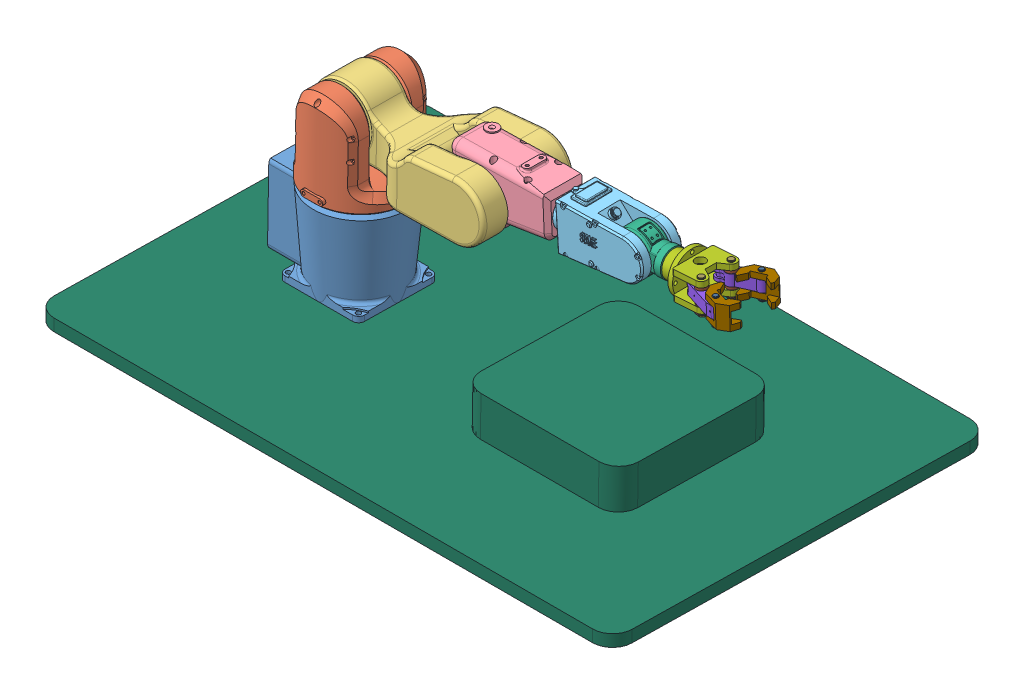
SolidWorks assembly ROBOT2, configuration 默认. Lengths in mm.
Overall size (1469.52 562.89 964.73).
25 component instances, 15 part files, 12 mates.
Components (placement in the parent):
- 0-1: 0 [默认] at (0 72.9247 -71.4969) x (1 0 0) z (0 0.017452 0.999848) size (299.76 239.19 271.11)
- 1_1-1: 1_1 [默认] at (0 293.8911 -75.3539) x (-0.009855 -0.017452 -0.999799) z (0.999951 -0.000172 -0.009854) size (332.05 234.42 332.05)
- 2-1: 2 [默认] at (349.9687 448.6466 -81.5049) x (-0.005084 0.999836 -0.017402) z (0.999939 0.004911 -0.009942) size (156.4 235.01 546.03)
- 3_1-1: 3_1 [默认] at (518.4298 478.9134 -83.6937) x (-0.998101 -0.060627 0.010897) z (0.060805 -0.998008 0.016821) size (250.17 103 166.59)
- 4-1: 4 [默认] at (708.4814 490.4577 -85.7686) x (0.998101 0.060627 -0.010897) z (0.01122 -0.004995 0.999925) size (240.42 124.25 113.23)
- 5_1-1: 5_1 [默认] at (708.4814 490.4577 -85.7686) x (-0.053404 0.998557 0.005588) z (-0.01122 0.004995 -0.999925) size (168.33 153.48 68)
- joint7-1: joint7 [默认] at (788.3622 494.7347 -86.6436) x (0.05357 -0.998517 0.009744) z (-0.99851 -0.053463 0.010937) size (105 164.84 211.36)
  - 14-1: 14 [默认] at origin size (105 105 121)
  - 18-1: 18 [默认] at (0 38.5 -107) x (0 0.344424 -0.938814) z (1 0 0) size (109.57 29 28)
  - 19-1: 19 [默认] at (0 69.5489 -159.698) x (0 0.330078 -0.943954) z (1 0 0) size (78 45 56)
  - 22-1: 22 [默认] at (35 59.1654 -163.3289) x (0 -0.811761 -0.583989) z (-1 0 0) size (18 18 66)
  - 24-1: 24 [默认] at (-21 38.5 -107) x (0 -0.533782 -0.845622) z (1 0 0) size (26 26 7)
  - 25-1: 25 [默认] at (44 38.5 -107) x (-1 0 0) z (0 -0.659078 -0.752075) size (82 21 21)
  - 24-2: 24 [默认] at (21 38.5 -107) x (0 -0.699829 -0.71431) z (-1 0 0) size (26 26 7)
  - 26-1: 26 [默认] at (26.3555 38.5 -107) x (0 -0.33616 0.941805) z (0 0.941805 0.33616) size (30 3 30)
  - 23-1: 23 [默认] at (28 59.1654 -163.3289) x (0 -0.043815 -0.99904) z (1 0 0) size (20 20 3)
  - 19-2: 19 [默认] at (0 -69.5489 -159.698) x (0 -0.330078 -0.943954) z (-1 0 0) size (78 45 56)
  - 18-2: 18 [默认] at (0 -38.5 -107) x (0 -0.344424 -0.938814) z (-1 0 0) size (109.57 29 28)
  - 22-2: 22 [默认] at (35 -59.1654 -163.3289) x (0 -0.811761 0.583989) z (-1 0 0) size (18 18 66)
  - 23-2: 23 [默认] at (31 -59.1654 -163.3289) x (0 0.043815 -0.99904) z (-1 0 0) size (20 20 3)
  - 25-2: 25 [默认] at (44 -38.5 -107) x (-1 0 0) z (0 -0.659078 0.752075) size (82 21 21)
  - 26-2: 26 [默认] at (26.3555 -38.5 -107) x (0 0.33616 0.941805) z (0 0.941805 -0.33616) size (30 3 30)
  - 24-3: 24 [默认] at (14 -38.5 -107) x (0 0.699829 -0.71431) z (1 0 0) size (26 26 7)
  - 24-4: 24 [默认] at (-14 -38.5 -107) x (0 0.533782 -0.845622) z (-1 0 0) size (26 26 7)
- 零件3-1: 零件3 [默认] at (0 72.9247 -71.4969) x (-1 0 0) z (0 -0.999848 0.017452) size (1469.52 959.99 280)
Mates (geometry in assembly coordinates):
- 重合1: coincident: plane of 0-1 through (0 291.8914 -75.319) normal (0 0.999848 -0.017452); plane of 1_1-1 through (0 291.8914 -75.319) normal (0 -0.999848 0.017452)
- 重合2: coincident: plane of 0-1 through (0 291.8914 -75.319) normal (0 0.999848 -0.017452); plane of 1_1-1 through (0 291.8914 -75.319) normal (0 -0.999848 0.017452)
- 同心1: concentric: circle of 0-1; circle of 1_1-1
- 重合3: coincident: plane of 1_1-1 through (0 293.8911 -75.3539) normal (-0.009855 -0.017452 -0.999799); plane of 2-1 through (349.9687 448.6466 -81.5049) normal (0.009855 0.017452 0.999799)
- 同心2: concentric: circle of 1_1-1; circle of 2-1
- 重合4: coincident: plane of 2-1 through (349.9687 448.6466 -81.5049) normal (0.009855 0.017452 0.999799); plane of 3_1-1 through (518.4298 478.9134 -83.6937) normal (-0.009855 -0.017452 -0.999799)
- 同心4: concentric: circle of 3_1-1; cylinder of 4-1 through (518.4298 478.9134 -83.6937) axis (0.998101 0.060627 -0.010897) radius 39.035
- 重合6: coincident: plane of 3_1-1 through (520.9773 428.1405 -132.8426) normal (0.998101 0.060627 -0.010897); plane of 4-1 through (518.4298 478.9134 -83.6937) normal (-0.998101 -0.060627 0.010897)
- 重合7: coincident: plane of 4-1 through (708.4814 490.4577 -85.7686) normal (0.01122 -0.004995 0.999925); plane of 5_1-1 through (708.4814 490.4577 -85.7686) normal (-0.01122 0.004995 -0.999925)
- 同心5: concentric: circle of 4-1; circle of 5_1-1
- 同心6: concentric: cylinder of 5_1-1 through (768.392 493.6654 -86.4248) axis (0.99851 0.053463 -0.010937) radius 34; cylinder of joint7-1/14-1 through (788.3622 494.7347 -86.6436) axis (0.99851 0.053463 -0.010937) radius 26
- 重合8: coincident: plane of 5_1-1 through (788.3622 494.7347 -86.6436) normal (0.99851 0.053463 -0.010937); plane of joint7-1/14-1 through (788.3622 494.7347 -86.6436) normal (-0.99851 -0.053463 0.010937)
